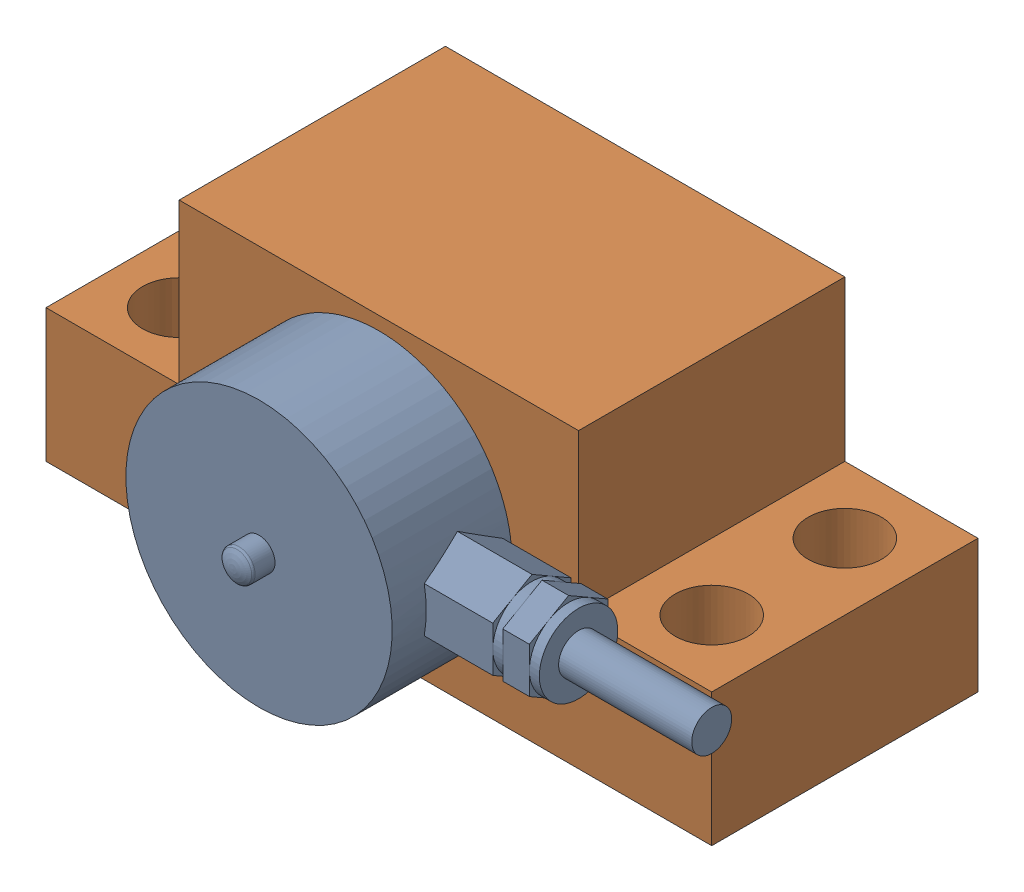
SolidWorks assembly loadcel yatay montaj, configuration Default. Lengths in mm.
Overall size (53.5 22 31).
2 component instances, 2 part files, 0 mates.
Components (placement in the parent):
- Mini_Loadcell-1: Mini_Loadcell [Default] at (0 11 19) x (-1 0 0) z (0 1 0) size (38.5 12 20)
- Loadcell yatay ayak-1: Loadcell yatay ayak [Default] at origin size (50 22 20)
